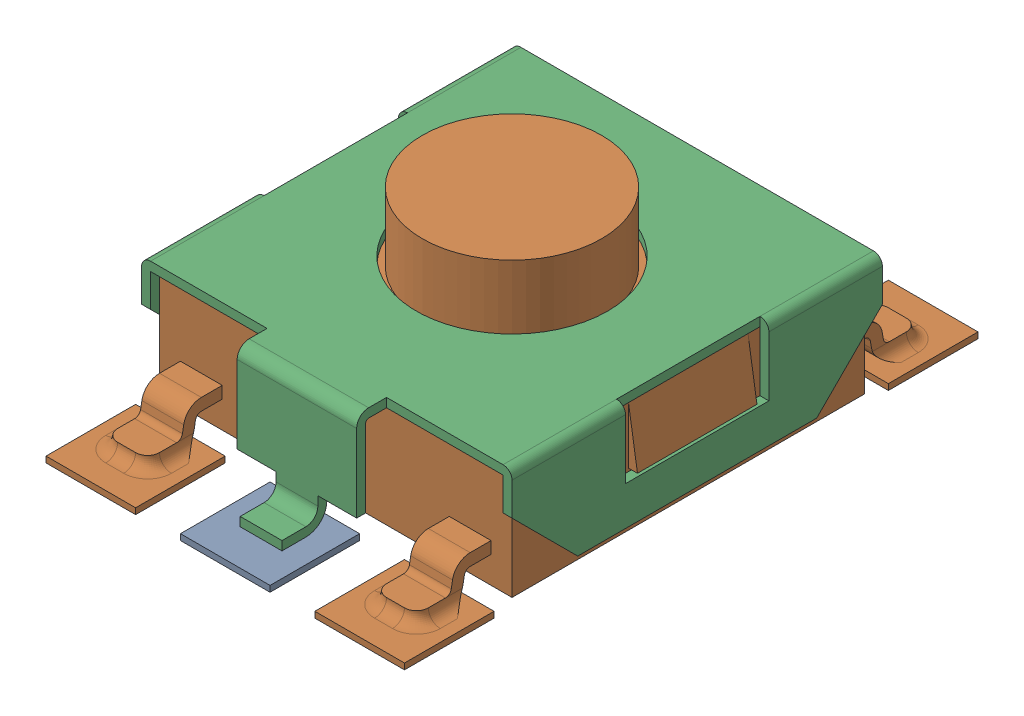
SolidWorks assembly RESET BUTTON, configuration Default. Lengths in mm.
Overall size (6.2 3.1 9.6).
2 component instances, 2 part files, 0 mates.
Components (placement in the parent):
- RESET CORE-1: RESET CORE [Default] at (0 0.1 0) x (-1 0 0) z (0 0 -1) size (6.2 3.1 9.6)
- RESET-1: RESET [Default] at (0 0.1 0) x (0 0 1) z (-1 0 0) size (7.3 2 6.2)
